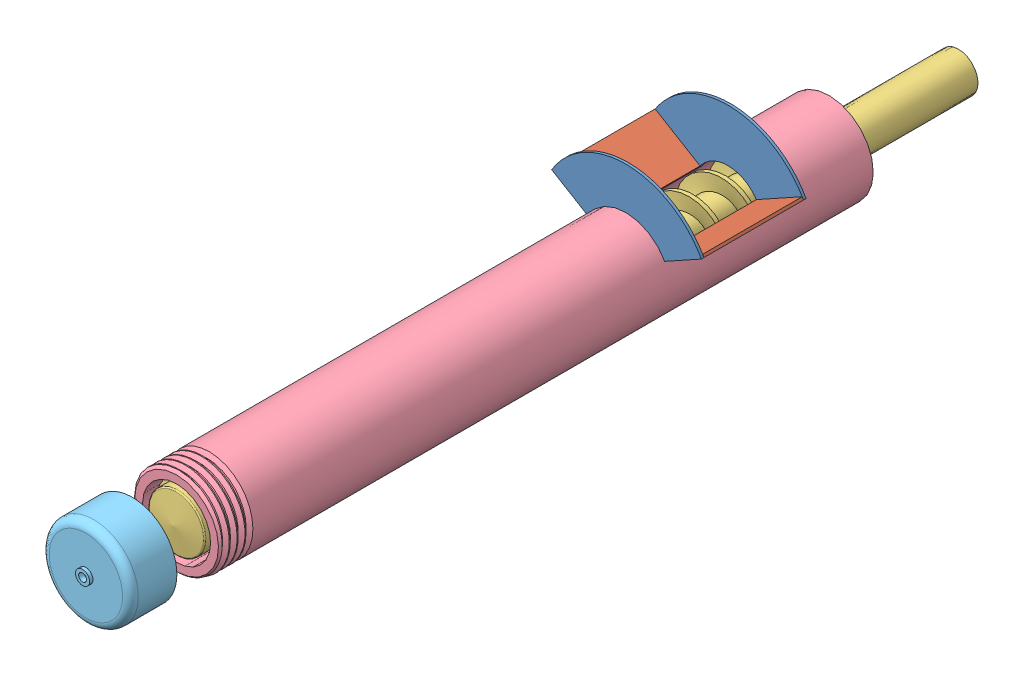
SolidWorks assembly assem screw, configuration Default. Lengths in mm.
Overall size (57.61 54.19 334.4).
7 component instances, 5 part files, 19 mates.
Components (placement in the parent):
- input nozel-1: input nozel [Default] at (-17 -17 -211.5) x (0.999852 -0.017222 0) z (-0.017222 -0.999852 0) size (57.16 1 26.5)
- noze; door-1: noze; door [Default] at (3.1137 -5.8447 -191.5) x (0.874508 0.485011 0) z (0 0 1) size (20 1 38)
- screw-1: screw [Default] at (-17 -17 -148.5) x (0 0 -1) z (0.976311 -0.216371 0) size (300 25.24 25.24)
- screw cover-1: screw cover [Default] at (-17 -17 -124.5) x (-0.999852 0.017222 0) z (-0.017222 -0.999852 0) size (34.01 250 35.75)
- input nozel-2: input nozel [Default] at (-17 -17 -172.5) x (0.999852 -0.017222 0) z (-0.017222 -0.999852 0) size (57.16 1 26.5)
- noze; door-2: noze; door [Default] at (-36.2027 -4.3014 -191.5) x (-0.857286 0.51484 0) z (0 0 1) size (20 1 38)
- nozzel-1: nozzel [Default] at (-17 -17 29.1651) x (0 0 -1) z (0.968407 -0.249376 0) size (19 34 34)
Mates (geometry in assembly coordinates):
- Coincident1: coincident aligned: plane of screw cover-1 through (-17 -17 0) normal (0 0 1)
- Tangent1: tangent aligned: cylinder of screw cover-1 through (-17 -17 -249) axis (0 0 1) radius 17
- Tangent2: tangent aligned: cylinder of screw cover-1 through (-17 -17 -249) axis (0 0 1) radius 17
- Concentric1: concentric aligned: cylinder of screw-1 through (-17 -17 1.5) axis (0 0 1) radius 7.5; cylinder of screw cover-1 through (-17 -17 -249) axis (0 0 1) radius 13
- Coincident2: coincident anti-aligned: circle of screw-1; plane of screw cover-1 through (-17 -17 -249) normal (0 0 -1)
- Coincident3: coincident aligned: cylinder of input nozel-1 through (-17 -17 -210.5) axis (0 0 -1) radius 13; circle of screw cover-1
- Coincident4: coincident anti-aligned: plane of input nozel-1 through (-45.2904 -0.0103 -210.5) normal (-0.51484 -0.857286 0); plane of screw cover-1 through (-17 -17 -171.5) normal (0.51484 0.857286 0)
- Coincident5: coincident anti-aligned: plane of input nozel-1 through (-17 -17 -211.5) normal (0 0 -1); plane of screw cover-1 through (-17 -17 -211.5) normal (0 0 1)
- Coincident7: coincident anti-aligned: plane of noze; door-1 through (3.1137 -5.8447 -191.5) normal (0.485011 -0.874508 0); plane of screw cover-1 through (-17 -17 -171.5) normal (-0.485011 0.874508 0)
- Coincident8: coincident anti-aligned: plane of input nozel-1 through (-17 -17 -210.5) normal (0 0 1); plane of noze; door-1 through (-6.1164 -9.8203 -210.5) normal (0 0 -1)
- Coincident9: coincident aligned: line of noze; door-1 through (-5.6314 -10.6949 -210.5) axis (0 0 1); line of screw cover-1 through (-5.6314 -10.6949 -211.5) axis (0 0 1)
- Coincident10: coincident anti-aligned: plane of noze; door-1 through (-6.1164 -9.8203 -172.5) normal (0 0 1); plane of input nozel-2 through (-17 -17 -172.5) normal (0 0 -1)
- Concentric3: concentric aligned: cylinder of input nozel-1 through (-17 -17 -210.5) axis (0 0 -1) radius 33; cylinder of input nozel-2 through (-17 -17 -171.5) axis (0 0 -1) radius 33
- Coincident11: coincident aligned: plane of input nozel-1 through (-45.2904 -0.0103 -210.5) normal (-0.51484 -0.857286 0); plane of input nozel-2 through (-45.2904 -0.0103 -171.5) normal (-0.51484 -0.857286 0)
- Coincident12: coincident anti-aligned: plane of screw cover-1 through (-17 -17 -171.5) normal (0.51484 0.857286 0); plane of noze; door-2 through (-36.7176 -5.1587 -191.5) normal (-0.51484 -0.857286 0)
- Coincident13: coincident anti-aligned: plane of input nozel-1 through (-17 -17 -210.5) normal (0 0 1); plane of noze; door-2 through (-28.1447 -10.3071 -210.5) normal (0 0 -1)
- Coincident14: coincident: line of screw cover-1 through (-28.1447 -10.3071 -171.5) axis (0 0 -1); plane of noze; door-2 through (-28.1447 -10.3071 -210.5) normal (0.857286 -0.51484 0)
- Concentric4: concentric aligned: cylinder of screw cover-1 through (-17 -17 -249) axis (0 0 1) radius 17; cylinder of nozzel-1 through (-17 -17 39.1651) axis (0 0 1) radius 17
- Distance1: distance = 253.3635 mm anti-aligned: plane of nozzel-1 through (-30.5577 -13.5087 34.6274) normal (0 0 1); plane of screw cover-1 through (-17 -17 -249) normal (0 0 -1)
